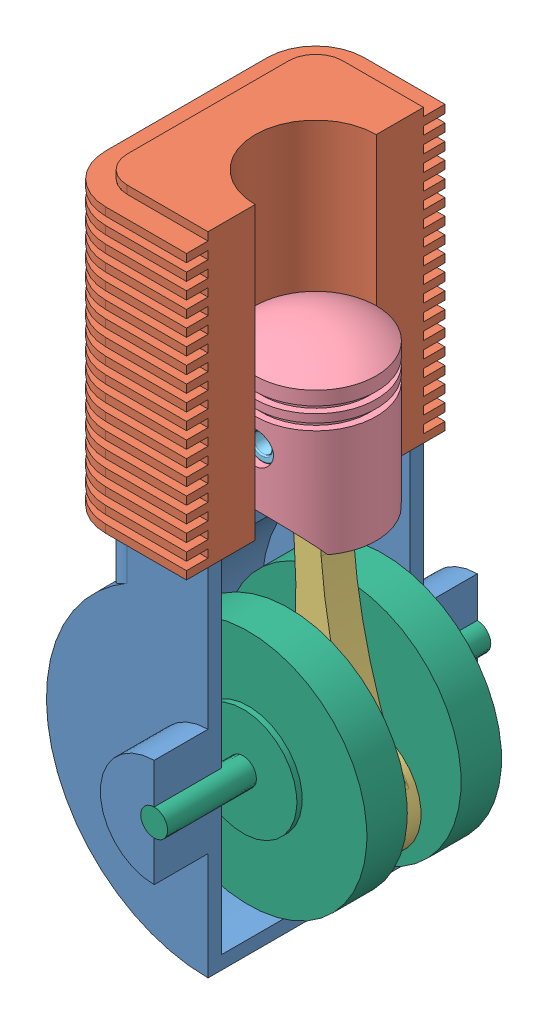
SolidWorks assembly Złożenie1, configuration Domyślna. Lengths in mm.
Overall size (104 240 120).
7 component instances, 7 part files, 12 mates.
Components (placement in the parent):
- Obudowa-1: Obudowa [Domyślna] at (-11.2767 9.695 167) size (60 132 120)
- Część1^Złożenie1-1: Część1^Złożenie1 [Domyślna] at origin (virtual)
- cylinder-1: cylinder [Domyślna] at (-11.2767 189.695 92) x (0 0 1) z (0 -1 0) size (96 48 108)
- Korbowod-1: Korbowod [Domyślna] at (-2.1417 -8.0969 132) x (-0.997098 -0.076125 0) z (0 0 -1) size (40 151 20)
- TLOK-1: TLOK [60] at (-11.2767 81.5549 132) x (-1 0 0) z (0 0 -1) size (45 62.26 45)
- Trzpien-1: Trzpien [Domyślna] at (-11.2767 111.5549 152) x (-0.999778 0.021057 0) z (0 0 -1) size (12 12 40)
- Część2-1: Część2 [Domyślna] at (-11.2767 9.695 72) x (-1 0 0) z (0 0 -1) size (88 88 120)
Mates (geometry in assembly coordinates):
- Wspólnie4: coincident anti-aligned: plane of Obudowa-1 through (-11.2767 81.695 172) normal (0 1 0); plane of cylinder-1 through (-11.2767 81.695 132) normal (0 -1 0)
- Wspólnie5: coincident aligned: plane of Obudowa-1 through (-11.2767 29.695 192) normal (1 0 0); plane of cylinder-1 through (-11.2767 81.695 154.5) normal (1 0 0)
- Wspólnie6: coincident aligned: plane of Obudowa-1 through (-11.2767 9.695 92) normal (0 0 -1); plane of cylinder-1 through (-11.2767 81.695 92) normal (0 0 -1)
- Koncentryczne2: concentric anti-aligned: cylinder of TLOK-1 through (-11.2767 111.5549 154.5) axis (0 0 -1) radius 6; cylinder of Trzpien-1 through (-11.2767 111.5549 112) axis (0 0 1) radius 6
- Szerokość3: width anti-aligned: plane of Trzpien-1 through (-11.2767 111.5549 152) normal (0 0 1); plane of TLOK-1 through (-11.2767 111.5549 112) normal (0 0 -1); plane of Trzpien-1 through (-11.2767 111.5549 142) normal (0 0 -1); plane of TLOK-1 through (-11.2767 111.5549 122) normal (0 0 1)
- Wspólnie8: coincident aligned: circle of Korbowod-1; circle of TLOK-1
- Koncentryczne3: concentric anti-aligned: cylinder of cylinder-1 through (-11.2767 81.695 132) axis (0 1 0) radius 22.5; cylinder of TLOK-1 through (-11.2767 81.5549 132) axis (0 -1 0) radius 22.5
- Ustalone1: in place: plane of Obudowa-1 through (-11.2767 9.695 72) normal (0 0 -1); plane of ? through (0 0 72) normal (0 0 -1); moOrthogonalPlaneRef_w of Obudowa-1 through (-11.2767 9.695 72) normal (0 0 -1); plane of ? through (0 0 72) normal (0 1 0); plane of Obudowa-1 through (-11.2767 9.695 72) normal (0 0 -1); plane of ? through (0 0 72) normal (-1 0 0); plane of Obudowa-1 through (-11.2767 9.695 72) normal (0 0 -1); unknown of Część2-1
- Wspólnie9: coincident aligned: plane of Obudowa-1; plane of Część2-1
- Wspólnie10: coincident aligned: moOrthogonalPlaneRef_w of Obudowa-1 through (-11.2767 9.695 72) normal (0 1 0); plane of Część2-1 through (-11.2767 9.695 72) normal (0 1 0)
- Wspólnie11: coincident anti-aligned: moOrthogonalPlaneRef_w of Obudowa-1 through (-11.2767 9.695 72) normal (1 0 0); plane of Część2-1 through (-11.2767 9.695 72) normal (-1 0 0)
- Koncentryczne5: concentric anti-aligned: cylinder of Korbowod-1 through (-2.1417 -8.0969 122) axis (0 0 1) radius 5; cylinder of Część2-1 through (-2.1417 -8.0969 142) axis (0 0 -1) radius 5
